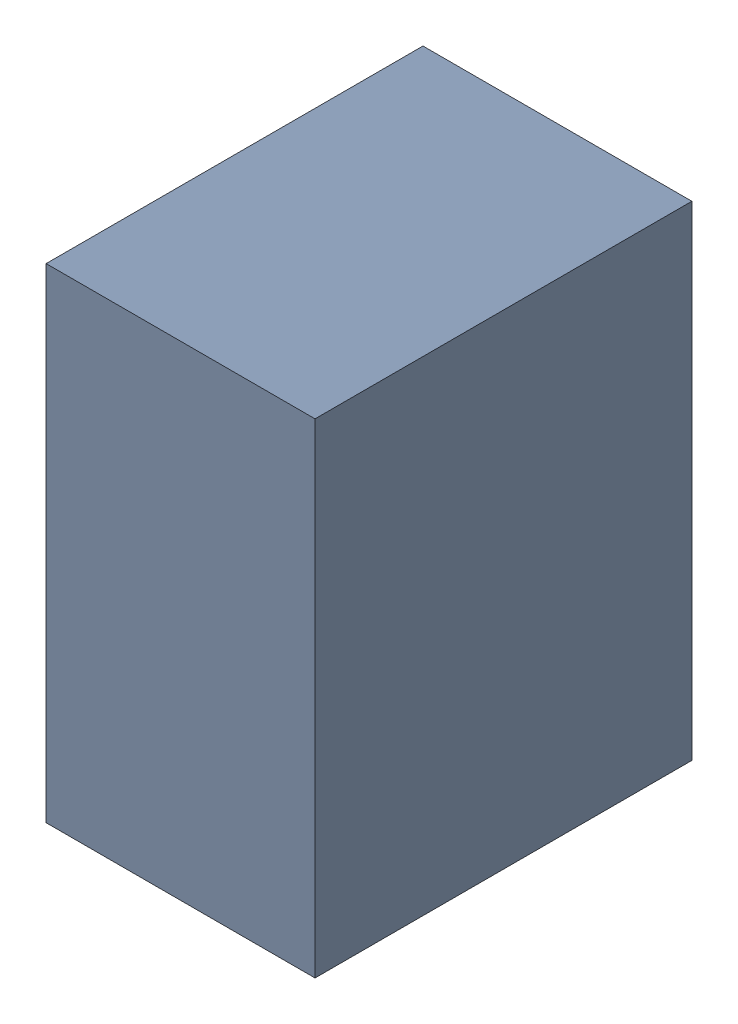
SolidWorks assembly C12, configuration Default. Lengths in mm.
Overall size (1 1.8 1.4).
3 component instances, 2 part files, 0 mates.
Components (placement in the parent):
- 1088883208-1: 1088883208 [Default] at (12.525 36.675 0) size (1 1.8 1.4)
  - Extruded-45-1: Extruded-45 [Default] at origin size (1 1.8 1.4)
- C0603-1: C0603 [Default] at (12.9251 35.8749 0) x (0 1 0) z (1 0 0) size (1.6 0.5 0.8)
